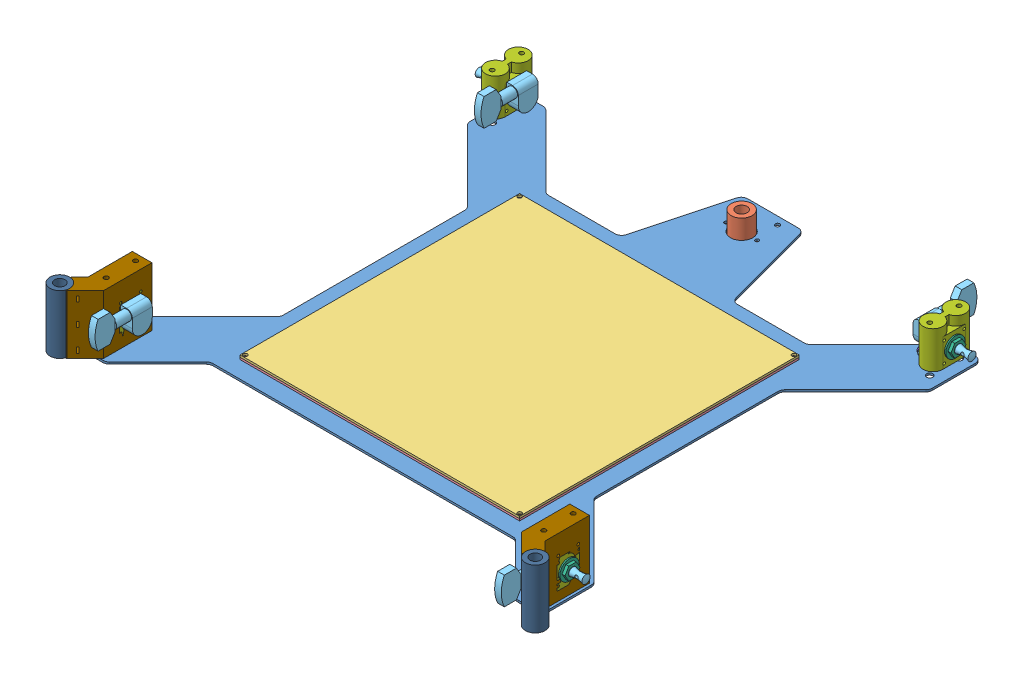
SolidWorks assembly Z-bed, configuration Default. Lengths in mm.
Overall size (381.84 48.52 374.34).
28 component instances, 10 part files, 35 mates.
Components (placement in the parent):
- core-XY bed-1: core-XY bed [Top] at origin size (353.81 1.52 354)
- motion nut-1: motion nut [Default] at (0 -3.5189 -170) x (-1 0 0) z (0 0 1) size (30 18 30)
- mk2b heated bed-1: mk2b heated bed [Default] at (0 1.5189 0) x (0 0 -1) z (1 0 0) size (214 1.6 214)
- heated bed spacer-1: heated bed spacer [Default] at origin size (214 1.52 214)
- tuning peg tensioner-1: tuning peg tensioner [Default] at (-151.11 17.5002 137.7502) x (0 1 0) z (-1 0 0) size (28.57 50.54 38.1)
  - TUNING PEG-1: TUNING PEG [Default] at origin size (28.38 45.1 38.1)
  - TUNING PEG RETAINER-1: TUNING PEG RETAINER [Default] at (0 0 12.74) x (0 -1 0) z (0 0 1) size (14.8 14.8 14.45)
  - tuning peg mount-1: tuning peg mount [Default] at (-0.0002 0.0002 8.89) x (-1 0 0) z (0 -1 0) size (28.5 15 32.5)
  - M2X10-1: M2X10 [Default] at (-7.6332 7.6332 6.731) x (0 0 1) z (1 0 0) size (12 3.8 3.8)
- tuning peg tensioner-2: tuning peg tensioner [Default] at (151.11 17.5002 -157.7502) x (0 1 0) z (1 0 0) size (28.57 50.54 38.1)
  - TUNING PEG-1: TUNING PEG [Default] at origin size (28.38 45.1 38.1)
  - TUNING PEG RETAINER-1: TUNING PEG RETAINER [Default] at (0 0 12.74) x (0 -1 0) z (0 0 1) size (14.8 14.8 14.45)
  - tuning peg mount-1: tuning peg mount [Default] at (-0.0002 0.0002 8.89) x (-1 0 0) z (0 -1 0) size (28.5 15 32.5)
  - M2X10-1: M2X10 [Default] at (-7.6332 7.6332 6.731) x (0 0 1) z (1 0 0) size (12 3.8 3.8)
- tuning peg tensioner-3: tuning peg tensioner [Default] at (-151.11 17.5002 -157.7498) x (0 1 0) z (-1 0 0) size (28.57 50.54 38.1)
  - TUNING PEG-1: TUNING PEG [Default] at origin size (28.38 45.1 38.1)
  - TUNING PEG RETAINER-1: TUNING PEG RETAINER [Default] at (0 0 12.74) x (0 -1 0) z (0 0 1) size (14.8 14.8 14.45)
  - tuning peg mount-1: tuning peg mount [Default] at (-0.0002 0.0002 8.89) x (-1 0 0) z (0 -1 0) size (28.5 15 32.5)
  - M2X10-1: M2X10 [Default] at (-7.6332 7.6332 6.731) x (0 0 1) z (1 0 0) size (12 3.8 3.8)
- tuning peg tensioner-4: tuning peg tensioner [Default] at (151.11 17.4998 137.7502) x (0 -1 0) z (1 0 0) size (28.57 50.54 38.1)
  - TUNING PEG-1: TUNING PEG [Default] at origin size (28.38 45.1 38.1)
  - TUNING PEG RETAINER-1: TUNING PEG RETAINER [Default] at (0 0 12.74) x (0 -1 0) z (0 0 1) size (14.8 14.8 14.45)
  - tuning peg mount-1: tuning peg mount [Default] at (-0.0002 0.0002 8.89) x (-1 0 0) z (0 -1 0) size (28.5 15 32.5)
  - M2X10-1: M2X10 [Default] at (-7.6332 7.6332 6.731) x (0 0 1) z (1 0 0) size (12 3.8 3.8)
- Bed bearing mount-2: Bed bearing mount [Default] at (167.5 0 126.5) x (-1 0 0) z (0 0 -1) size (22 45 56)
- Bed bearing mount-1: Bed bearing mount [Default] at (-167.5 45 126.5) x (1 0 0) z (0 0 -1) size (22 45 56)
- linear bearing-1: linear bearing [Default] at (-182 0 170) size (15 45 15)
- linear bearing-2: linear bearing [Default] at (182 0 170) x (0.847343 0 0.531046) z (-0.531046 0 0.847343) size (15 45 15)
Mates (geometry in assembly coordinates):
- Concentric56: concentric anti-aligned: cylinder of linear bearing-1 through (-182 45 170) axis (0 -1 0) radius 7.5; cylinder of Bed bearing mount-1 through (-182 0 170) axis (0 1 0) radius 7.5
- Concentric57: concentric anti-aligned: cylinder of core-XY bed-1 through (-167.5 -1.5189 149) axis (0 -1 0) radius 2.4; cylinder of Bed bearing mount-1 through (-167.5 0 149) axis (0 1 0) radius 1.7
- Coincident101: coincident anti-aligned: plane of core-XY bed-1 through (0 0 0) normal (0 1 0); plane of Bed bearing mount-1 through (-167.5 0 126.5) normal (0 -1 0)
- Coincident103: coincident aligned: plane of linear bearing-1 through (-182 45 170) normal (0 1 0); plane of Bed bearing mount-1 through (-167.5 45 126.5) normal (0 1 0)
- Concentric52: concentric aligned: cylinder of linear bearing-2 through (182 45 170) axis (0 -1 0) radius 7.5; cylinder of Bed bearing mount-2 through (182 45 170) axis (0 -1 0) radius 7.5
- Coincident100: coincident aligned: plane of linear bearing-2 through (182 45 170) normal (0 1 0); plane of Bed bearing mount-2 through (167.5 45 126.5) normal (0 1 0)
- Coincident75: coincident anti-aligned: plane of mk2b heated bed-1 through (0 1.5189 0) normal (0 -1 0); plane of heated bed spacer-1 through (0 1.5189 0) normal (0 1 0)
- Coincident76: coincident aligned: plane of mk2b heated bed-1 through (-107 3.1189 -107) normal (-1 0 0); plane of heated bed spacer-1 through (-107 1.5189 -107) normal (-1 0 0)
- Coincident77: coincident aligned: plane of mk2b heated bed-1 through (-107 3.1189 -107) normal (0 0 -1); plane of heated bed spacer-1 through (107 1.5189 -107) normal (0 0 -1)
- Concentric44: concentric: cylinder of mk2b heated bed-1 through (105 -190.9751 -105) axis (0 1 0) radius 1.55; cylinder of core-XY bed-1 through (105 -194.094 -105) axis (0 1 0) radius 1.8
- Concentric45: concentric: cylinder of mk2b heated bed-1 through (105 -190.9751 105) axis (0 1 0) radius 1.55; cylinder of core-XY bed-1 through (105 -194.094 105) axis (0 1 0) radius 1.8
- Concentric48: concentric aligned: cylinder of mk2b heated bed-1 through (105 3.1189 -105) axis (0 1 0) radius 1.55; cylinder of core-XY bed-1 through (105 0 -105) axis (0 1 0) radius 1.8
- Concentric49: concentric aligned: cylinder of mk2b heated bed-1 through (-105 3.1189 -105) axis (0 1 0) radius 1.55; cylinder of core-XY bed-1 through (-105 0 -105) axis (0 1 0) radius 1.8
- Coincident78: coincident anti-aligned: plane of heated bed spacer-1 through (0 0 0) normal (0 -1 0); plane of core-XY bed-1 through (0 0 0) normal (0 1 0)
- Coincident84: coincident: plane of tuning peg tensioner-1/tuning peg mount-1 through (-175 0 154) normal (0 -1 0); plane of core-XY bed-1 through (0 0 0) normal (0 1 0)
- Concentric78: concentric anti-aligned: cylinder of tuning peg tensioner-1/tuning peg mount-1 through (-167.5 35 126.5) axis (0 1 0) radius 1.65; cylinder of core-XY bed-1 through (-167.5 -1.5189 126.5) axis (0 -1 0) radius 2.4
- Concentric79: concentric anti-aligned: cylinder of tuning peg tensioner-1/tuning peg mount-1 through (-167.5 35 149) axis (0 1 0) radius 1.65; cylinder of core-XY bed-1 through (-167.5 -1.5189 149) axis (0 -1 0) radius 2.4
- Coincident85: coincident: plane of core-XY bed-1 through (0 0 0) normal (0 1 0); plane of tuning peg tensioner-2/tuning peg mount-1 through (175 0 -174) normal (0 -1 0)
- Coincident91: coincident anti-aligned: plane of core-XY bed-1 through (0 0 0) normal (0 1 0); plane of tuning peg tensioner-4/tuning peg mount-1 through (175 0 154) normal (0 -1 0)
- Concentric51: concentric: cylinder of core-XY bed-1 through (11.825 -210.615 -170) axis (0 1 0) radius 1.375; cylinder of motion nut-1 through (11.825 -202.615 -170) axis (0 -1 0) radius 1.25
- Concentric55: concentric aligned: cylinder of core-XY bed-1 through (167.5 -1.5189 149) axis (0 -1 0) radius 2.4; cylinder of Bed bearing mount-2 through (167.5 45 149) axis (0 -1 0) radius 1.7
- Coincident98: coincident anti-aligned: plane of core-XY bed-1 through (0 0 0) normal (0 1 0); plane of Bed bearing mount-2 through (167.5 0 126.5) normal (0 -1 0)
- Concentric75: concentric anti-aligned: cylinder of core-XY bed-1 through (167.5 -1.5189 -169) axis (0 -1 0) radius 2.4; cylinder of tuning peg tensioner-2/tuning peg mount-1 through (167.5 35 -169) axis (0 1 0) radius 1.65
- Concentric76: concentric aligned: cylinder of core-XY bed-1 through (167.5 -1.5189 126.5) axis (0 -1 0) radius 2.4; cylinder of tuning peg tensioner-4/tuning peg mount-1 through (167.5 0 126.5) axis (0 -1 0) radius 1.65
- Concentric77: concentric aligned: cylinder of core-XY bed-1 through (167.5 -1.5189 149) axis (0 -1 0) radius 2.4; cylinder of tuning peg tensioner-4/tuning peg mount-1 through (167.5 0 149) axis (0 -1 0) radius 1.65
- Concentric124: concentric anti-aligned: cylinder of core-XY bed-1 through (11.825 -1.5189 -170) axis (0 1 0) radius 1.375; cylinder of motion nut-1 through (11.825 6.4811 -170) axis (0 -1 0) radius 1.25
- Concentric133: concentric anti-aligned: cylinder of core-XY bed-1 through (167.5 -1.5189 -146.5) axis (0 -1 0) radius 2.4; cylinder of tuning peg tensioner-2/tuning peg mount-1 through (167.5 35 -146.5) axis (0 1 0) radius 1.65
- Concentric134: concentric anti-aligned: cylinder of core-XY bed-1 through (-167.5 -1.5189 -169) axis (0 -1 0) radius 2.4; cylinder of tuning peg tensioner-3/tuning peg mount-1 through (-167.5 35 -169) axis (0 1 0) radius 1.65
- Concentric135: concentric anti-aligned: cylinder of core-XY bed-1 through (-167.5 -1.5189 -146.5) axis (0 -1 0) radius 2.4; cylinder of tuning peg tensioner-3/tuning peg mount-1 through (-167.5 35 -146.5) axis (0 1 0) radius 1.65
- Coincident167: coincident: plane of core-XY bed-1 through (0 0 0) normal (0 1 0); plane of tuning peg tensioner-3/tuning peg mount-1 through (-175 0 -141.5) normal (0 -1 0)
- Coincident204: coincident anti-aligned: plane of core-XY bed-1 through (0 -1.5189 0) normal (0 -1 0); plane of motion nut-1 through (0 -1.5189 -170) normal (0 1 0)
- Coincident205: coordinate: point of ?
- Concentric136: concentric anti-aligned: cylinder of core-XY bed-1 through (-11.825 -1.5189 -170) axis (0 1 0) radius 1.375; cylinder of motion nut-1 through (-11.825 6.4811 -170) axis (0 -1 0) radius 1.25
- Concentric137: concentric anti-aligned: cylinder of core-XY bed-1 through (-167.5 -1.5189 126.5) axis (0 -1 0) radius 2.4; cylinder of Bed bearing mount-1 through (-167.5 0 126.5) axis (0 1 0) radius 1.7
- Concentric138: concentric aligned: cylinder of core-XY bed-1 through (167.5 -1.5189 126.5) axis (0 -1 0) radius 2.4; cylinder of Bed bearing mount-2 through (167.5 45 126.5) axis (0 -1 0) radius 1.7
